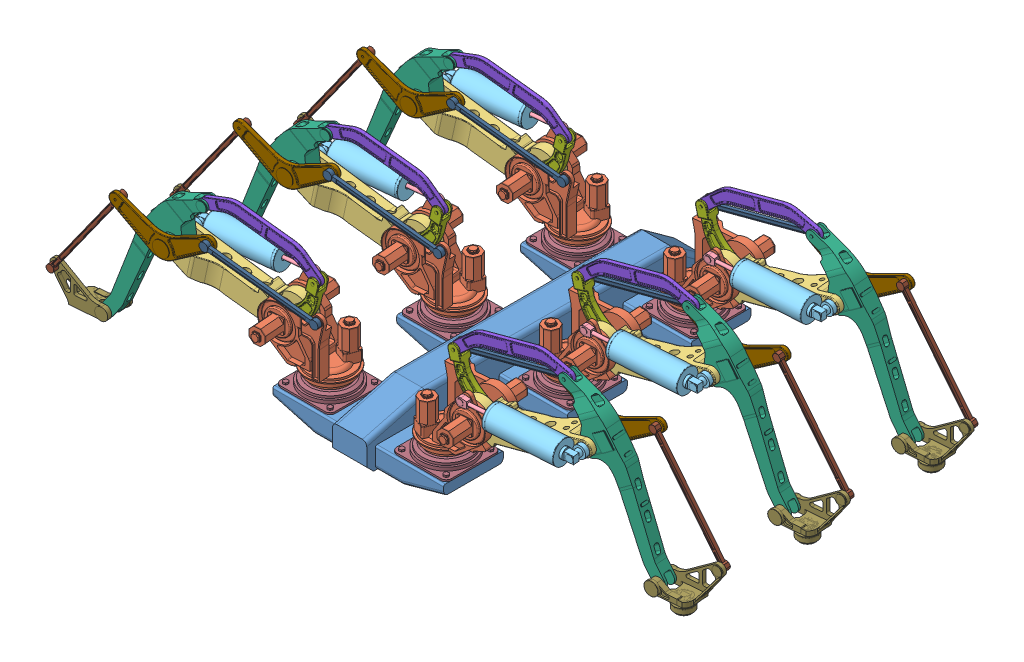
SolidWorks assembly SPIDER_ROBOT, configuration Default. Lengths in mm.
Overall size (7165.6 1940.67 4061.2).
79 component instances, 13 part files, 18 mates.
Components (placement in the parent):
- Part3^SPIDER_ROBOT-1: Part3^SPIDER_ROBOT [Default] at (-620.6704 1944.5642 727.4031) x (1 0 0) z (0 0 -1) size (2000 520.29 3956.06) (virtual)
- M-410iB-300 -1: M-410iB-300  [Default] at (-140.6704 1757.7059 377.4031) size (3223.76 1940.67 1084.52) (flexible)
  - M-410iB-300-02-1: M-410iB-300-02 [Default] at (0 392.791 0) x (0.996593 0 -0.082475) z (0.082475 0 0.996593) size (882 808.47 1015.24)
  - M-410iB-300-03-1: M-410iB-300-03 [Default] at (388.1377 757.7954 -38.5711) x (0.198184 -0.980028 -0.016401) z (0.082475 0 0.996593) size (419.18 1495 341.99)
  - M-410iB-300-04-1: M-410iB-300-04 [Default] at (410.5482 1022.7765 222.787) x (-0.082475 0 -0.996593) z (-0.018655 -0.999825 0.001544) size (121.92 852.86 97.99)
  - M-410iB-300-05-1: M-410iB-300-05 [Default] at (735.4445 1016.6728 195.8995) x (-0.018655 -0.999825 0.001544) z (0.082475 0 0.996593) size (270.16 938.24 280.42)
  - M-410iB-300-06-1: M-410iB-300-06 [Default] at (1583.8828 1000.4057 -86.6094) x (0.57223 -0.818725 -0.047356) z (0.082475 0 0.996593) size (2019.02 410 281.01)
  - M-410iB-300-07-1: M-410iB-300-07 [Default] at (388.1738 757.7954 -38.1344) x (0.577872 -0.814725 -0.047823) z (0.082475 0 0.996593) size (725 234.73 271.78)
  - M-410iB-300-08-1: M-410iB-300-08 [Default] at (63.1336 1252.2501 -78.2549) x (0.201289 -0.97939 -0.016658) z (0.082475 0 0.996593) size (272.14 1335.77 50)
  - M-410iB-300-09-1: M-410iB-300-09 [Default] at (1560.013 1000.4057 -375.0421) x (0.996593 -0.000938 -0.082475) z (0.082475 0 0.996593) size (1140.98 447.8 123.83)
  - M-410iB-300-10-1: M-410iB-300-10 [Default] at (-137.0165 1029.791 -309.7871) x (0.198758 -0.979911 -0.016449) z (0.082475 0 0.996593) size (95.32 1315.31 48.01)
  - M-410iB-300-11-1: M-410iB-300-11 [Default] at (2061.0965 1269.9367 -385.6712) x (0.57223 -0.818725 -0.047356) z (0.082475 0 0.996593) size (1386.99 82.5 64.26)
  - M-410iB-300-12-1: M-410iB-300-12 [Default] at (2579.0039 -223.176 -202.5391) x (0.996593 -0.000938 -0.082475) z (0.082475 0 0.996593) size (642.38 494 365.33)
  - ArmBase-1: ArmBase [Default] at origin size (640 101.46 640)
- M-410iB-300 -2: M-410iB-300  [Default] at (-140.6704 1757.7059 -1072.5969) size (3223.76 1940.67 1084.52) (flexible)
  - M-410iB-300-02-1: M-410iB-300-02 [Default] at (0 392.791 0) x (0.996593 0 -0.082475) z (0.082475 0 0.996593) size (882 808.47 1015.24)
  - M-410iB-300-03-1: M-410iB-300-03 [Default] at (388.1377 757.7954 -38.5711) x (0.198184 -0.980028 -0.016401) z (0.082475 0 0.996593) size (419.18 1495 341.99)
  - M-410iB-300-04-1: M-410iB-300-04 [Default] at (410.5482 1022.7765 222.787) x (-0.082475 0 -0.996593) z (-0.018655 -0.999825 0.001544) size (121.92 852.86 97.99)
  - M-410iB-300-05-1: M-410iB-300-05 [Default] at (735.4445 1016.6728 195.8995) x (-0.018655 -0.999825 0.001544) z (0.082475 0 0.996593) size (270.16 938.24 280.42)
  - M-410iB-300-06-1: M-410iB-300-06 [Default] at (1583.8828 1000.4057 -86.6094) x (0.57223 -0.818725 -0.047356) z (0.082475 0 0.996593) size (2019.02 410 281.01)
  - M-410iB-300-07-1: M-410iB-300-07 [Default] at (388.1738 757.7954 -38.1344) x (0.577872 -0.814725 -0.047823) z (0.082475 0 0.996593) size (725 234.73 271.78)
  - M-410iB-300-08-1: M-410iB-300-08 [Default] at (63.1336 1252.2501 -78.2549) x (0.201289 -0.97939 -0.016658) z (0.082475 0 0.996593) size (272.14 1335.77 50)
  - M-410iB-300-09-1: M-410iB-300-09 [Default] at (1560.013 1000.4057 -375.0421) x (0.996593 -0.000938 -0.082475) z (0.082475 0 0.996593) size (1140.98 447.8 123.83)
  - M-410iB-300-10-1: M-410iB-300-10 [Default] at (-137.0165 1029.791 -309.7871) x (0.198758 -0.979911 -0.016449) z (0.082475 0 0.996593) size (95.32 1315.31 48.01)
  - M-410iB-300-11-1: M-410iB-300-11 [Default] at (2061.0965 1269.9367 -385.6712) x (0.57223 -0.818725 -0.047356) z (0.082475 0 0.996593) size (1386.99 82.5 64.26)
  - M-410iB-300-12-1: M-410iB-300-12 [Default] at (2579.0039 -223.176 -202.5391) x (0.996593 -0.000938 -0.082475) z (0.082475 0 0.996593) size (642.38 494 365.33)
  - ArmBase-1: ArmBase [Default] at origin size (640 101.46 640)
- M-410iB-300 -3: M-410iB-300  [Default] at (-140.6704 1757.7059 -2522.5969) size (3223.76 1940.67 1084.52) (flexible)
  - M-410iB-300-02-1: M-410iB-300-02 [Default] at (0 392.791 0) x (0.996593 0 -0.082475) z (0.082475 0 0.996593) size (882 808.47 1015.24)
  - M-410iB-300-03-1: M-410iB-300-03 [Default] at (388.1377 757.7954 -38.5711) x (0.198184 -0.980028 -0.016401) z (0.082475 0 0.996593) size (419.18 1495 341.99)
  - M-410iB-300-04-1: M-410iB-300-04 [Default] at (410.5482 1022.7765 222.787) x (-0.082475 0 -0.996593) z (-0.018655 -0.999825 0.001544) size (121.92 852.86 97.99)
  - M-410iB-300-05-1: M-410iB-300-05 [Default] at (735.4445 1016.6728 195.8995) x (-0.018655 -0.999825 0.001544) z (0.082475 0 0.996593) size (270.16 938.24 280.42)
  - M-410iB-300-06-1: M-410iB-300-06 [Default] at (1583.8828 1000.4057 -86.6094) x (0.57223 -0.818725 -0.047356) z (0.082475 0 0.996593) size (2019.02 410 281.01)
  - M-410iB-300-07-1: M-410iB-300-07 [Default] at (388.1738 757.7954 -38.1344) x (0.577872 -0.814725 -0.047823) z (0.082475 0 0.996593) size (725 234.73 271.78)
  - M-410iB-300-08-1: M-410iB-300-08 [Default] at (63.1336 1252.2501 -78.2549) x (0.201289 -0.97939 -0.016658) z (0.082475 0 0.996593) size (272.14 1335.77 50)
  - M-410iB-300-09-1: M-410iB-300-09 [Default] at (1560.013 1000.4057 -375.0421) x (0.996593 -0.000938 -0.082475) z (0.082475 0 0.996593) size (1140.98 447.8 123.83)
  - M-410iB-300-10-1: M-410iB-300-10 [Default] at (-137.0165 1029.791 -309.7871) x (0.198758 -0.979911 -0.016449) z (0.082475 0 0.996593) size (95.32 1315.31 48.01)
  - M-410iB-300-11-1: M-410iB-300-11 [Default] at (2061.0965 1269.9367 -385.6712) x (0.57223 -0.818725 -0.047356) z (0.082475 0 0.996593) size (1386.99 82.5 64.26)
  - M-410iB-300-12-1: M-410iB-300-12 [Default] at (2579.0039 -223.176 -202.5391) x (0.996593 -0.000938 -0.082475) z (0.082475 0 0.996593) size (642.38 494 365.33)
  - ArmBase-1: ArmBase [Default] at origin size (640 101.46 640)
- M-410iB-300 -7: M-410iB-300  [Default] at (-1500.6704 1757.7059 -2522.5969) x (-1 0 0) z (0 0 -1) size (3223.76 1940.67 1084.52) (flexible)
  - M-410iB-300-02-1: M-410iB-300-02 [Default] at (0 392.791 0) x (0.996593 0 -0.082475) z (0.082475 0 0.996593) size (882 808.47 1015.24)
  - M-410iB-300-03-1: M-410iB-300-03 [Default] at (388.1377 757.7954 -38.5711) x (0.198184 -0.980028 -0.016401) z (0.082475 0 0.996593) size (419.18 1495 341.99)
  - M-410iB-300-04-1: M-410iB-300-04 [Default] at (410.5482 1022.7765 222.787) x (-0.082475 0 -0.996593) z (-0.018655 -0.999825 0.001544) size (121.92 852.86 97.99)
  - M-410iB-300-05-1: M-410iB-300-05 [Default] at (735.4445 1016.6728 195.8995) x (-0.018655 -0.999825 0.001544) z (0.082475 0 0.996593) size (270.16 938.24 280.42)
  - M-410iB-300-06-1: M-410iB-300-06 [Default] at (1583.8828 1000.4057 -86.6094) x (0.57223 -0.818725 -0.047356) z (0.082475 0 0.996593) size (2019.02 410 281.01)
  - M-410iB-300-07-1: M-410iB-300-07 [Default] at (388.1738 757.7954 -38.1344) x (0.577872 -0.814725 -0.047823) z (0.082475 0 0.996593) size (725 234.73 271.78)
  - M-410iB-300-08-1: M-410iB-300-08 [Default] at (63.1336 1252.2501 -78.2549) x (0.201289 -0.97939 -0.016658) z (0.082475 0 0.996593) size (272.14 1335.77 50)
  - M-410iB-300-09-1: M-410iB-300-09 [Default] at (1560.013 1000.4057 -375.0421) x (0.996593 -0.000938 -0.082475) z (0.082475 0 0.996593) size (1140.98 447.8 123.83)
  - M-410iB-300-10-1: M-410iB-300-10 [Default] at (-137.0165 1029.791 -309.7871) x (0.198758 -0.979911 -0.016449) z (0.082475 0 0.996593) size (95.32 1315.31 48.01)
  - M-410iB-300-11-1: M-410iB-300-11 [Default] at (2061.0965 1269.9367 -385.6712) x (0.57223 -0.818725 -0.047356) z (0.082475 0 0.996593) size (1386.99 82.5 64.26)
  - M-410iB-300-12-1: M-410iB-300-12 [Default] at (2579.0039 -223.176 -202.5391) x (0.996593 -0.000938 -0.082475) z (0.082475 0 0.996593) size (642.38 494 365.33)
  - ArmBase-1: ArmBase [Default] at origin size (640 101.46 640)
- M-410iB-300 -8: M-410iB-300  [Default] at (-1500.6704 1757.7059 -1072.5969) x (-1 0 0) z (0 0 -1) size (3223.76 1940.67 1084.52) (flexible)
  - M-410iB-300-02-1: M-410iB-300-02 [Default] at (0 392.791 0) x (0.996593 0 -0.082475) z (0.082475 0 0.996593) size (882 808.47 1015.24)
  - M-410iB-300-03-1: M-410iB-300-03 [Default] at (388.1377 757.7954 -38.5711) x (0.198184 -0.980028 -0.016401) z (0.082475 0 0.996593) size (419.18 1495 341.99)
  - M-410iB-300-04-1: M-410iB-300-04 [Default] at (410.5482 1022.7765 222.787) x (-0.082475 0 -0.996593) z (-0.018655 -0.999825 0.001544) size (121.92 852.86 97.99)
  - M-410iB-300-05-1: M-410iB-300-05 [Default] at (735.4445 1016.6728 195.8995) x (-0.018655 -0.999825 0.001544) z (0.082475 0 0.996593) size (270.16 938.24 280.42)
  - M-410iB-300-06-1: M-410iB-300-06 [Default] at (1583.8828 1000.4057 -86.6094) x (0.57223 -0.818725 -0.047356) z (0.082475 0 0.996593) size (2019.02 410 281.01)
  - M-410iB-300-07-1: M-410iB-300-07 [Default] at (388.1738 757.7954 -38.1344) x (0.577872 -0.814725 -0.047823) z (0.082475 0 0.996593) size (725 234.73 271.78)
  - M-410iB-300-08-1: M-410iB-300-08 [Default] at (63.1336 1252.2501 -78.2549) x (0.201289 -0.97939 -0.016658) z (0.082475 0 0.996593) size (272.14 1335.77 50)
  - M-410iB-300-09-1: M-410iB-300-09 [Default] at (1560.013 1000.4057 -375.0421) x (0.996593 -0.000938 -0.082475) z (0.082475 0 0.996593) size (1140.98 447.8 123.83)
  - M-410iB-300-10-1: M-410iB-300-10 [Default] at (-137.0165 1029.791 -309.7871) x (0.198758 -0.979911 -0.016449) z (0.082475 0 0.996593) size (95.32 1315.31 48.01)
  - M-410iB-300-11-1: M-410iB-300-11 [Default] at (2061.0965 1269.9367 -385.6712) x (0.57223 -0.818725 -0.047356) z (0.082475 0 0.996593) size (1386.99 82.5 64.26)
  - M-410iB-300-12-1: M-410iB-300-12 [Default] at (2579.0039 -223.176 -202.5391) x (0.996593 -0.000938 -0.082475) z (0.082475 0 0.996593) size (642.38 494 365.33)
  - ArmBase-1: ArmBase [Default] at origin size (640 101.46 640)
- M-410iB-300 -9: M-410iB-300  [Default] at (-1500.6704 1757.7059 377.4031) x (-1 0 0) z (0 0 -1) size (3223.76 1940.67 1084.52) (flexible)
  - M-410iB-300-02-1: M-410iB-300-02 [Default] at (0 392.791 0) x (0.996593 0 -0.082475) z (0.082475 0 0.996593) size (882 808.47 1015.24)
  - M-410iB-300-03-1: M-410iB-300-03 [Default] at (388.1377 757.7954 -38.5711) x (0.198184 -0.980028 -0.016401) z (0.082475 0 0.996593) size (419.18 1495 341.99)
  - M-410iB-300-04-1: M-410iB-300-04 [Default] at (410.5482 1022.7765 222.787) x (-0.082475 0 -0.996593) z (-0.018655 -0.999825 0.001544) size (121.92 852.86 97.99)
  - M-410iB-300-05-1: M-410iB-300-05 [Default] at (735.4445 1016.6728 195.8995) x (-0.018655 -0.999825 0.001544) z (0.082475 0 0.996593) size (270.16 938.24 280.42)
  - M-410iB-300-06-1: M-410iB-300-06 [Default] at (1583.8828 1000.4057 -86.6094) x (0.57223 -0.818725 -0.047356) z (0.082475 0 0.996593) size (2019.02 410 281.01)
  - M-410iB-300-07-1: M-410iB-300-07 [Default] at (388.1738 757.7954 -38.1344) x (0.577872 -0.814725 -0.047823) z (0.082475 0 0.996593) size (725 234.73 271.78)
  - M-410iB-300-08-1: M-410iB-300-08 [Default] at (63.1336 1252.2501 -78.2549) x (0.201289 -0.97939 -0.016658) z (0.082475 0 0.996593) size (272.14 1335.77 50)
  - M-410iB-300-09-1: M-410iB-300-09 [Default] at (1560.013 1000.4057 -375.0421) x (0.996593 -0.000938 -0.082475) z (0.082475 0 0.996593) size (1140.98 447.8 123.83)
  - M-410iB-300-10-1: M-410iB-300-10 [Default] at (-137.0165 1029.791 -309.7871) x (0.198758 -0.979911 -0.016449) z (0.082475 0 0.996593) size (95.32 1315.31 48.01)
  - M-410iB-300-11-1: M-410iB-300-11 [Default] at (2061.0965 1269.9367 -385.6712) x (0.57223 -0.818725 -0.047356) z (0.082475 0 0.996593) size (1386.99 82.5 64.26)
  - M-410iB-300-12-1: M-410iB-300-12 [Default] at (2579.0039 -223.176 -202.5391) x (0.996593 -0.000938 -0.082475) z (0.082475 0 0.996593) size (642.38 494 365.33)
  - ArmBase-1: ArmBase [Default] at origin size (640 101.46 640)
Mates (geometry in assembly coordinates):
- Coincident1: coincident anti-aligned: plane of Part3^SPIDER_ROBOT-1 through (-620.6704 1944.5642 727.4031) normal (0 1 0); plane of M-410iB-300 -1/ArmBase-1 through (-140.6704 1944.5642 377.4031) normal (0 -1 0)
- Distance1: distance = 30 mm aligned: plane of M-410iB-300 -1/ArmBase-1 through (-460.6704 1944.5642 697.4031) normal (0 0 1); plane of Part3^SPIDER_ROBOT-1 through (-620.6704 1694.5642 727.4031) normal (0 0 1)
- Coincident3: coincident: plane of Part3^SPIDER_ROBOT-1 through (179.3296 1694.5642 727.4031) normal (1 0 0); moEndPointRef_w of M-410iB-300 -1/ArmBase-1
- Coincident4_issue: coincident anti-aligned: moEndPointRef_w of M-410iB-300 -2/ArmBase-1; plane of Part3^SPIDER_ROBOT-1 through (179.3296 1694.5642 -722.5969) normal (1 0 0)
- Coincident5: coincident anti-aligned: plane of Part3^SPIDER_ROBOT-1 through (-620.6704 1944.5642 -722.5969) normal (0 1 0); plane of M-410iB-300 -2/ArmBase-1 through (-140.6704 1944.5642 -1072.5969) normal (0 -1 0)
- Distance2: distance = 30 mm aligned: plane of M-410iB-300 -2/ArmBase-1 through (-460.6704 1944.5642 -1392.5969) normal (0 0 -1); plane of Part3^SPIDER_ROBOT-1 through (-620.6704 1694.5642 -1422.5969) normal (0 0 -1)
- Coincident7: coincident anti-aligned: plane of Part3^SPIDER_ROBOT-1 through (-620.6704 1944.5642 -2172.5969) normal (0 1 0); plane of M-410iB-300 -3/ArmBase-1 through (-140.6704 1944.5642 -2522.5969) normal (0 -1 0)
- Distance3: distance = 30 mm aligned: plane of M-410iB-300 -3/ArmBase-1 through (-460.6704 1944.5642 -2842.5969) normal (0 0 -1); plane of Part3^SPIDER_ROBOT-1 through (-620.6704 1694.5642 -2872.5969) normal (0 0 -1)
- Coincident9: coincident: plane of Part3^SPIDER_ROBOT-1 through (179.3296 1694.5642 -2172.5969) normal (1 0 0); moEndPointRef_w of M-410iB-300 -3/ArmBase-1
- Coincident11: coincident aligned: plane of Part3^SPIDER_ROBOT-1 through (-1820.6704 1694.5642 -2172.5969) normal (-1 0 0); plane of M-410iB-300 -7/ArmBase-1 through (-1820.6704 1944.5642 -2202.5969) normal (-1 0 0)
- Coincident12: coincident anti-aligned: plane of Part3^SPIDER_ROBOT-1 through (-1020.6704 1944.5642 -722.5969) normal (0 1 0); plane of M-410iB-300 -8/ArmBase-1 through (-1500.6704 1944.5642 -1072.5969) normal (0 -1 0)
- Coincident14: coincident anti-aligned: plane of Part3^SPIDER_ROBOT-1 through (-1020.6704 1944.5642 727.4031) normal (0 1 0); plane of M-410iB-300 -9/ArmBase-1 through (-1500.6704 1944.5642 377.4031) normal (0 -1 0)
- Coincident16: coincident aligned: plane of Part3^SPIDER_ROBOT-1 through (-1820.6704 1694.5642 727.4031) normal (-1 0 0); plane of M-410iB-300 -9/ArmBase-1 through (-1820.6704 1944.5642 697.4031) normal (-1 0 0)
- Coincident17: coincident anti-aligned: plane of Part3^SPIDER_ROBOT-1 through (-1020.6704 1944.5642 -2172.5969) normal (0 1 0); plane of M-410iB-300 -7/ArmBase-1 through (-1500.6704 1944.5642 -2522.5969) normal (0 -1 0)
- Coincident18: coincident aligned: plane of Part3^SPIDER_ROBOT-1 through (-1820.6704 1694.5642 -722.5969) normal (-1 0 0); plane of M-410iB-300 -8/ArmBase-1 through (-1820.6704 1944.5642 -752.5969) normal (-1 0 0)
- Distance4: distance = 30 mm aligned: plane of Part3^SPIDER_ROBOT-1 through (-1020.6704 1694.5642 -2872.5969) normal (0 0 -1); plane of M-410iB-300 -7/ArmBase-1 through (-1180.6704 1944.5642 -2842.5969) normal (0 0 -1)
- Distance5: distance = 30 mm aligned: plane of Part3^SPIDER_ROBOT-1 through (-1020.6704 1694.5642 -1422.5969) normal (0 0 -1); plane of M-410iB-300 -8/ArmBase-1 through (-1180.6704 1944.5642 -1392.5969) normal (0 0 -1)
- Distance6: distance = 30 mm aligned: plane of Part3^SPIDER_ROBOT-1 through (-1020.6704 1694.5642 27.4031) normal (0 0 -1); plane of M-410iB-300 -9/ArmBase-1 through (-1180.6704 1944.5642 57.4031) normal (0 0 -1)
